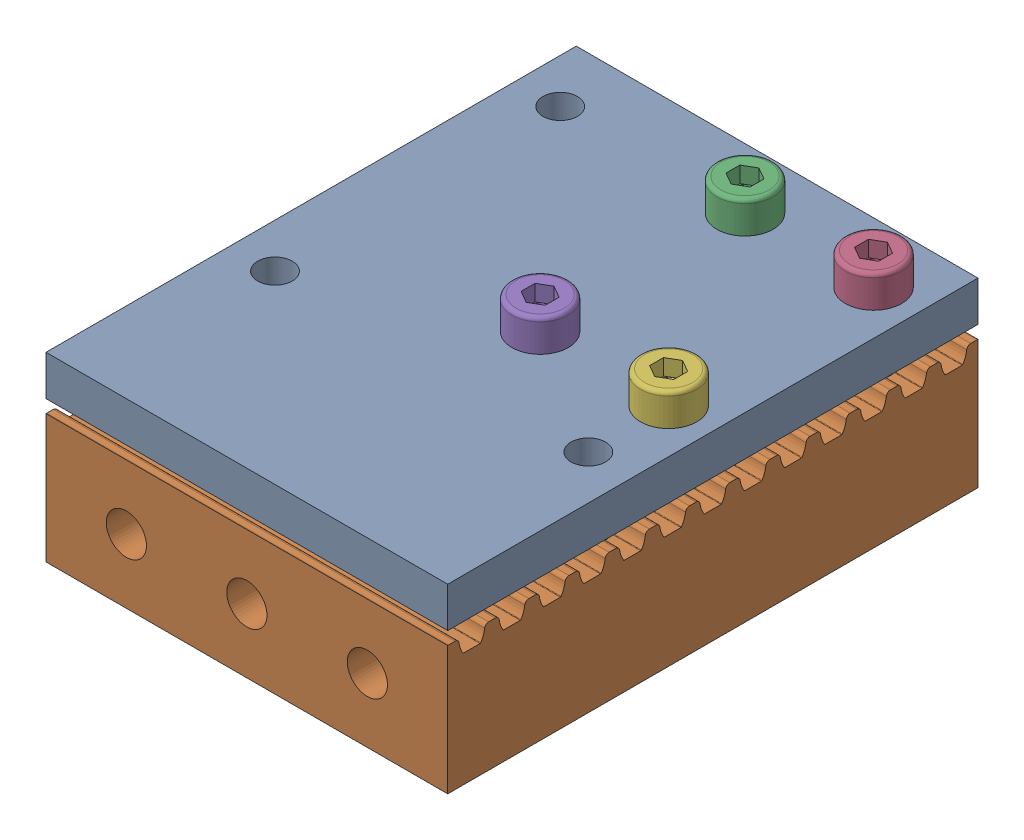
SolidWorks assembly ECY11-S5M-100, configuration 默认. Lengths in mm.
Overall size (50 22.6 66).
10 component instances, 4 part files, 0 mates.
Components (placement in the parent):
- _ECY11-S5M100-B                                100 S5M-1: _ECY11-S5M100-B                                100 S5M [默认] at origin size (50 5 66)
- _ECY11-S5M100-C                                100 S5M-1: _ECY11-S5M100-C                                100 S5M [默认] at origin size (50 16.01 66)
- _ECY11-S5M100-D                                100 S5M-1: _ECY11-S5M100-D                                100 S5M [默认] at (-8 4 -25.5) x (1 0 0) z (0 1 0) size (7 7 19) (hidden)
- _ECY11-S5M100-D                                100 S5M-2: _ECY11-S5M100-D                                100 S5M [默认] at (8 4 -25.5) x (1 0 0) z (0 1 0) size (7 7 19) (hidden)
- _ECY11-S5M100-D                                100 S5M-5: _ECY11-S5M100-D                                100 S5M [默认] at (-8 4 0) x (1 0 0) z (0 1 0) size (7 7 19) (hidden)
- _ECY11-S5M100-D                                100 S5M-6: _ECY11-S5M100-D                                100 S5M [默认] at (8 4 0) x (1 0 0) z (0 1 0) size (7 7 19) (hidden)
- _ECY11-S5M100-E                                100 S5M-1: _ECY11-S5M100-E                                100 S5M [默认] at (-8 -12.6 -25.5) x (1 0 0) z (0 0 -1) size (7.02 2.22 8.1) (hidden)
- _ECY11-S5M100-E                                100 S5M-2: _ECY11-S5M100-E                                100 S5M [默认] at (8 -12.6 -25.5) x (1 0 0) z (0 0 -1) size (7.02 2.22 8.1) (hidden)
- _ECY11-S5M100-E                                100 S5M-5: _ECY11-S5M100-E                                100 S5M [默认] at (-8 -12.6 0) x (1 0 0) z (0 0 -1) size (7.02 2.22 8.1) (hidden)
- _ECY11-S5M100-E                                100 S5M-6: _ECY11-S5M100-E                                100 S5M [默认] at (8 -12.6 0) x (1 0 0) z (0 0 -1) size (7.02 2.22 8.1) (hidden)
